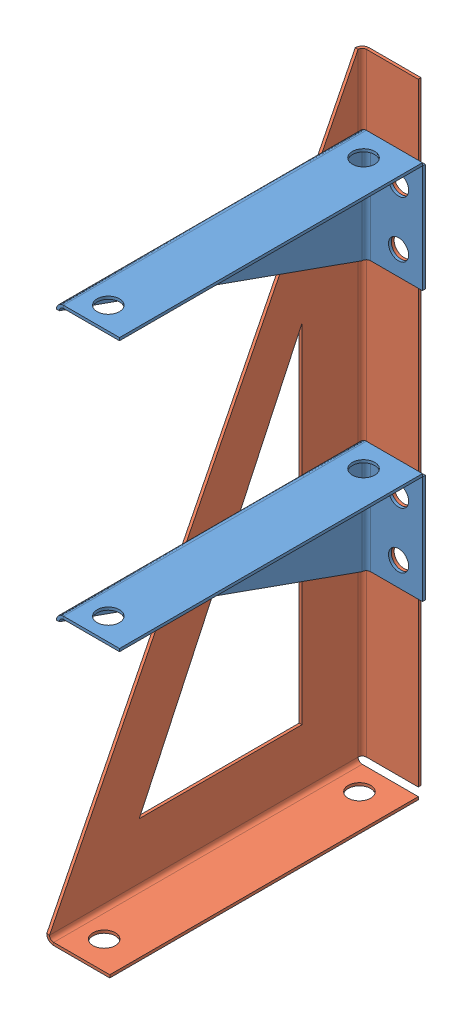
SolidWorks assembly CircuitRackAssembly, configuration Default. Lengths in mm.
Overall size (16.48 110.5 56.24).
3 component instances, 2 part files, 4 mates.
Components (placement in the parent):
- CircuitRackHolderR-1: CircuitRackHolderR [Default] at (26.2638 36.3492 31.7724) size (11.24 20.5 55.24)
- CircuitRackHolderR-2: CircuitRackHolderR [Default] at (26.2638 84.3492 31.7724) size (11.24 20.5 55.24)
- CircuitRack-2: CircuitRack [side2] at (5.3784 -14.384 32.7618) size (15.24 110.5 56.24)
Mates (geometry in assembly coordinates):
- Coincident4: coincident anti-aligned: plane of CircuitRackHolderR-1 through (26.2638 36.3492 10.0723) normal (0 0 -1); plane of CircuitRack-2 through (5.3784 -14.384 10.0723) normal (0 0 1)
- Concentric1: concentric anti-aligned: circle of CircuitRackHolderR-1; circle of CircuitRack-2
- Coincident6: coincident anti-aligned: plane of CircuitRackHolderR-2 through (26.2638 84.3492 10.0723) normal (0 0 -1); plane of CircuitRack-2 through (5.3784 -14.384 10.0723) normal (0 0 1)
- Concentric2: concentric anti-aligned: circle of CircuitRackHolderR-2; circle of CircuitRack-2
